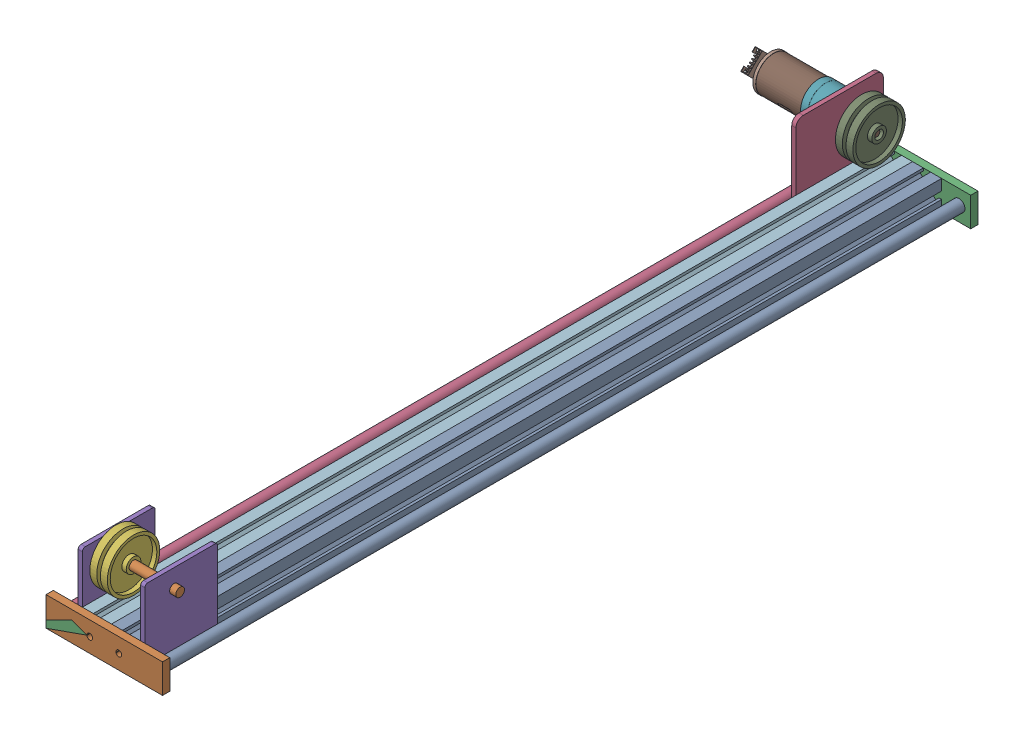
SolidWorks assembly ensamble base, configuration Predeterminado. Lengths in mm.
Overall size (124.8 67.96 562.46).
13 component instances, 8 part files, 31 mates.
Components (placement in the parent):
- Cilinfro guia-1: Cilinfro guia [Predeterminado] at (12 10 552.9) x (0.220892 -0.975298 0) z (0 0 1) size (8 8 555)
- Eje poleas-1: Eje poleas [Predeterminado] at (-42.9 42.5 530) x (0 0 -1) z (1 0 0) size (6 6 50)
- Placa extremos-1: Placa extremos [Predeterminado] at (-60 0 550) size (80 20 5)
- Placa motriz-1: Placa motriz [Predeterminado] at (-40 0 60) x (0 0 -1) z (1 0 0) size (60 65 2.9)
- Placa polea libre-1: Placa polea libre [Predeterminado] at (-40 0 500) x (0 0 1) z (-1 0 0) size (50 55 2.9)
- Polea libre-1: Polea libre [Predeterminado] at (-24.9 42.5 530) size (12 36 36)
- Polea y motor-1: Polea y motor [Predeterminado] at (-78.7757 95.5177 67.3666) x (-1 0 0) z (0 -0.70804 -0.706173) size (79.9 36 36)
- riel extruido-1: riel extruido [Predeterminado] at (-30 10 550) size (20 20 550)
- riel extruido-2: riel extruido [Predeterminado] at (-10 10 550) size (20 20 550)
- Placa extremos-2: Placa extremos [Predeterminado] at (-60 0 550) size (80 20 5)
- Placa extremos-3: Placa extremos [Predeterminado] at (20 0 0) x (-1 0 0) z (0 0 -1) size (80 20 5)
- Cilinfro guia-2: Cilinfro guia [Predeterminado] at (-52 10 552.9) x (0.220892 -0.975298 0) z (0 0 1) size (8 8 555)
- Placa polea libre-2: Placa polea libre [Predeterminado] at (2.9 0 500) x (0 0 1) z (-1 0 0) size (50 55 2.9)
Mates (geometry in assembly coordinates):
- Coincidente1: coincident anti-aligned: plane of riel extruido-2 through (-20 0 0) normal (0 -1 0)
- Coincidente2: coincident anti-aligned: plane of riel extruido-2 through (-17.4 5.0042 0) normal (0 0 -1)
- Coincidente3: coincident aligned: plane of riel extruido-2 through (0 12.5 0) normal (1 0 0)
- Coincidente4: coincident aligned: plane of riel extruido-1 through (-40 20 0) normal (0 1 0); plane of riel extruido-2 through (0 20 0) normal (0 1 0)
- Coincidente5: coincident anti-aligned: plane of riel extruido-1 through (-20 12.5 0) normal (1 0 0); plane of riel extruido-2 through (-20 12.5 0) normal (-1 0 0)
- Coincidente6: coincident aligned: plane of riel extruido-1 through (-37.4 5.0042 0) normal (0 0 -1); plane of riel extruido-2 through (-17.4 5.0042 0) normal (0 0 -1)
- Coincidente7: coincident anti-aligned: plane of Placa extremos-1 through (-60 0 550) normal (0 0 -1); plane of riel extruido-2 through (-17.4 5.0042 550) normal (0 0 1)
- Concéntrica1: concentric anti-aligned: cylinder of Placa extremos-1 through (-30 10 555) axis (0 0 -1) radius 2; cylinder of riel extruido-1 through (-30 10 0) axis (0 0 1) radius 2.1
- Concéntrica2: concentric aligned: circle of Placa extremos-1; cylinder of riel extruido-2 through (-10 10 0) axis (0 0 1) radius 2.1
- Concéntrica3: concentric anti-aligned: cylinder of Cilinfro guia-1 through (12 10 -2.1) axis (0 0 1) radius 4; cylinder of Placa extremos-1 through (12 10 555) axis (0 0 -1) radius 4.05
- Coincidente8: coincident anti-aligned: plane of Cilinfro guia-1 through (12 10 552.9) normal (0 0 1); plane of Placa extremos-1 through (13 10 552.9) normal (0 0 -1)
- Coincidente10: coincident anti-aligned: plane of riel extruido-2 through (-17.4 5.0042 0) normal (0 0 -1); plane of Placa extremos-3 through (20 0 0) normal (0 0 1)
- Concéntrica4: concentric anti-aligned: cylinder of riel extruido-1 through (-30 10 0) axis (0 0 1) radius 2.1; circle of Placa extremos-3
- Concéntrica5: concentric aligned: cylinder of riel extruido-2 through (-10 10 0) axis (0 0 1) radius 2.1; cylinder of Placa extremos-3 through (-10 10 -5) axis (0 0 1) radius 2
- Concéntrica6: concentric aligned: cylinder of Placa extremos-3 through (-52 10 -5) axis (0 0 1) radius 4.05; cylinder of Cilinfro guia-2 through (-52 10 -2.1) axis (0 0 1) radius 4
- Coincidente11: coincident anti-aligned: plane of Placa extremos-1 through (-52 10 552.9) normal (0 0 -1); plane of Cilinfro guia-2 through (-52 10 552.9) normal (0 0 1)
- Coincidente12: coincident anti-aligned: plane of Placa motriz-1 through (-40 0 60) normal (1 0 0); plane of riel extruido-1 through (-40 12.5 0) normal (-1 0 0)
- Coincidente14: coincident anti-aligned: plane of Placa motriz-1 through (-42.9 0 0) normal (0 0 -1); plane of Placa extremos-3 through (20 0 0) normal (0 0 1)
- Coincidente15: coincident aligned: plane of Placa motriz-1 through (-42.9 0 60) normal (0 -1 0); plane of riel extruido-1 through (-40 0 0) normal (0 -1 0)
- Coincidente16: coincident anti-aligned: plane of Placa polea libre-1 through (-40 0 500) normal (1 0 0); plane of riel extruido-1 through (-40 0 0) normal (-1 0 0)
- Coincidente17: coincident aligned: plane of Placa polea libre-1 through (-42.9 0 500) normal (0 -1 0); plane of riel extruido-1 through (-40 0 0) normal (0 -1 0)
- Coincidente18: coincident anti-aligned: plane of Placa extremos-1 through (-60 0 550) normal (0 0 -1); plane of Placa polea libre-1 through (-42.9 0 550) normal (0 0 1)
- Concéntrica7: concentric anti-aligned: cylinder of Placa motriz-1 through (-42.9 42.5 18) axis (1 0 0) radius 3; cylinder of Polea y motor-1 through (-40.4 42.5 18) axis (-1 0 0) radius 3.5
- Coincidente19: coincident anti-aligned: plane of Placa motriz-1 through (-42.9 0 60) normal (-1 0 0); plane of Polea y motor-1 through (-42.9 42.5 18) normal (1 0 0)
- Concéntrica8: concentric anti-aligned: cylinder of Eje poleas-1 through (7.1 42.5 530) axis (-1 0 0) radius 3; cylinder of Placa polea libre-1 through (-42.9 42.5 530) axis (1 0 0) radius 3
- Coincidente20: coincident aligned: plane of Eje poleas-1 through (-42.9 42.5 530) normal (-1 0 0); plane of Placa polea libre-1 through (-42.9 0 500) normal (-1 0 0)
- Concéntrica9: concentric anti-aligned: cylinder of Eje poleas-1 through (7.1 42.5 530) axis (-1 0 0) radius 3; cylinder of Polea libre-1 through (-24.9 42.5 530) axis (1 0 0) radius 3
- Coincidente21: coincident aligned: plane of Polea libre-1 through (-24.9 60.5 530) normal (1 0 0); plane of Polea y motor-1 through (-24.9 54.5765 7.5043) normal (1 0 0)
- Coincidente22: coincident anti-aligned: plane of riel extruido-2 through (0 12.5 0) normal (1 0 0); plane of Placa polea libre-2 through (0 -2.9891 500) normal (-1 0 0)
- Coincidente24: coincident anti-aligned: plane of Placa extremos-1 through (-60 0 550) normal (0 0 -1); plane of Placa polea libre-2 through (0 0 550) normal (0 0 1)
- Concéntrica10: concentric anti-aligned: cylinder of Eje poleas-1 through (7.1 42.5 530) axis (-1 0 0) radius 3; cylinder of Placa polea libre-2 through (0 42.5 530) axis (1 0 0) radius 3
